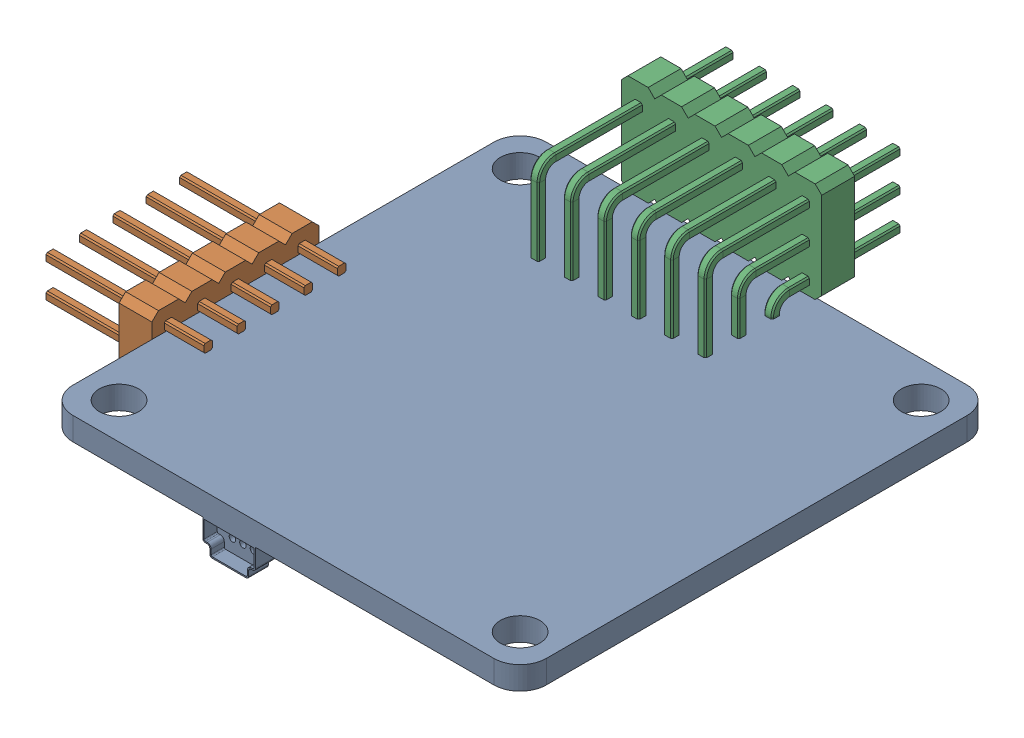
SolidWorks assembly Assem1, configuration Default. Lengths in mm.
Overall size (45 11.89 42.6).
3 component instances, 3 part files, 8 mates.
Components (placement in the parent):
- distribuation part-2: distribuation part [Default] at (-6.1993 4.3209 -0.6523) x (-1 0 0) z (0 0 1) size (36 4.12 36)
- electrical unit-3: electrical unit [Default] at (-21.1993 2.1759 -2.0823) x (0 1 0) z (0 0 1) size (5.08 12 12.7)
- electrical unit 2-1: electrical unit 2 [Default] at (-2.2293 1.4159 -15.8523) x (0 0 1) z (-1 0 0) size (14.8 10.68 15.24)
Mates (geometry in assembly coordinates):
- Width2: width: plane of distribuation part-2 through (9.8007 4.3209 -16.6523) normal (0 1 0); plane of electrical unit-3 through (9.8007 2.5709 -16.6523) normal (0 -1 0); plane of distribuation part-2 through (-33.1993 4.3909 7.8527) normal (0 -1 0); plane of electrical unit-3 through (-33.1993 2.5009 7.8527) normal (0 1 0)
- Coincident3: coincident: plane of distribuation part-2 through (-24.1993 2.5709 -16.6523) normal (-1 0 0); plane of electrical unit-3 through (-24.1993 2.1759 -2.0823) normal (1 0 0)
- Distance2: distance = 8 mm aligned: plane of electrical unit-3 through (-26.6993 5.4733 9.3477) normal (0 0 1); plane of distribuation part-2 through (9.8007 2.5709 17.3477) normal (0 0 1)
- Parallel1: parallel: plane of distribuation part-2 through (11.8007 2.5709 -16.6523) normal (1 0 0); plane of electrical unit 2-1 through (-0.9593 11.5909 -20.8523) normal (1 0 0)
- Parallel2: parallel: plane of distribuation part-2 through (9.8007 2.5709 -18.6523) normal (0 0 -1); plane of electrical unit 2-1 through (-2.2293 1.4159 -20.8523) normal (0 0 -1)
- Distance3: distance = 0.3 mm: plane of distribuation part-2 through (9.8007 2.5709 -18.6523) normal (0 0 -1); plane of electrical unit 2-1 through (-2.2293 1.4159 -18.3523) normal (0 0 1)
- Distance4: distance = 8 mm: plane of distribuation part-2 through (-24.1993 2.5709 -16.6523) normal (-1 0 0); plane of electrical unit 2-1 through (-16.1993 11.5909 -20.8523) normal (-1 0 0)
- Distance5: distance = 1.9 mm aligned: plane of distribuation part-2 through (9.8007 2.5709 -16.6523) normal (0 -1 0); plane of electrical unit 2-1 through (-15.6993 4.4709 -20.8523) normal (0 -1 0)
